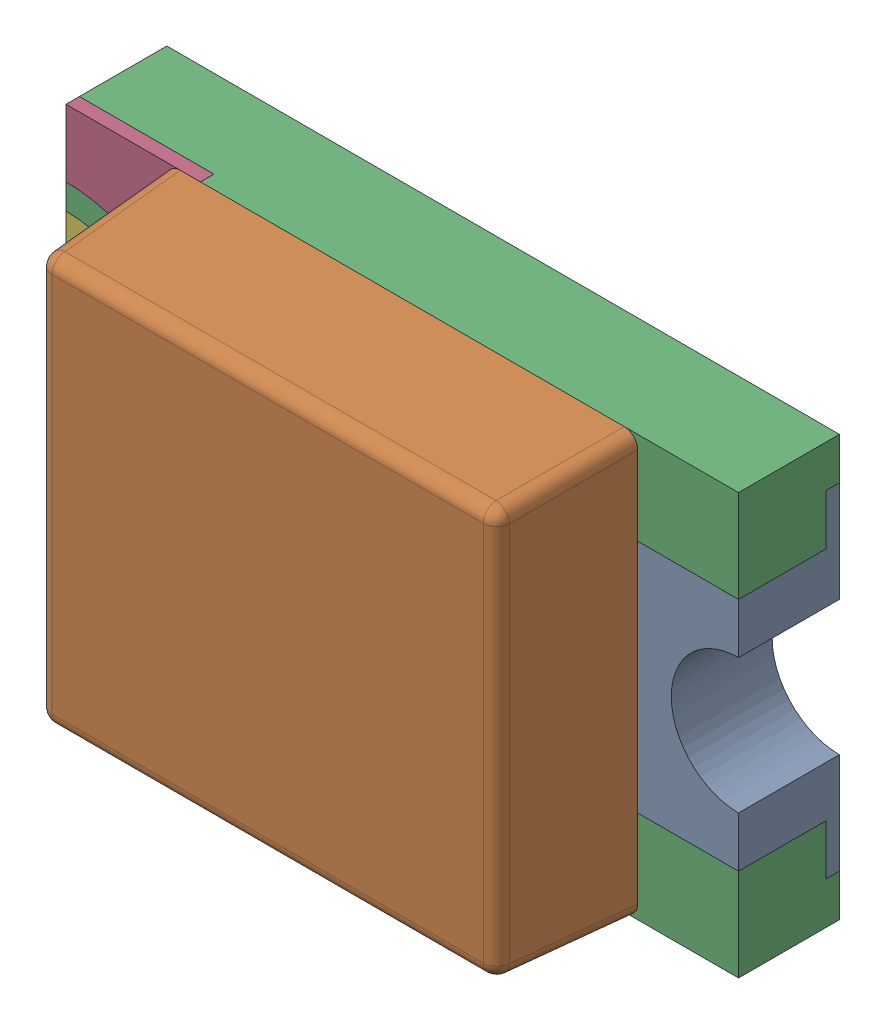
SolidWorks assembly Power, configuration Standard. Lengths in mm.
Overall size (2 1.25 0.7).
7 component instances, 5 part files, 0 mates.
Components (placement in the parent):
- WL-SMCW_0805_LED-1: WL-SMCW_0805_LED [Standard] at (-11.1648 27.3652 -0.02) x (1 0 0) z (0 0 1) size (2 1.25 0.7)
  - base-1: base [Standard] at (0.8 0 0) x (-1 0 0) z (0 0 1) size (0.4 1 0.3)
  - cover-1: cover [Standard] at (0 0 0.3) size (1.4 1.25 0.4)
  - housing_3-1: housing_3 [Standard] at origin size (2 1.25 0.3)
  - marking-1: marking [Standard] at (-0.8 0.525 0.26) size (0.4 0.48 0.04)
  - marking-2: marking [Standard] at (-0.8 -0.525 0.3) x (1 0 0) z (0 0 -1) size (0.4 0.48 0.04)
  - base_2-1: base_2 [Standard] at (-0.8 0 0) size (0.4 1 0.3)
